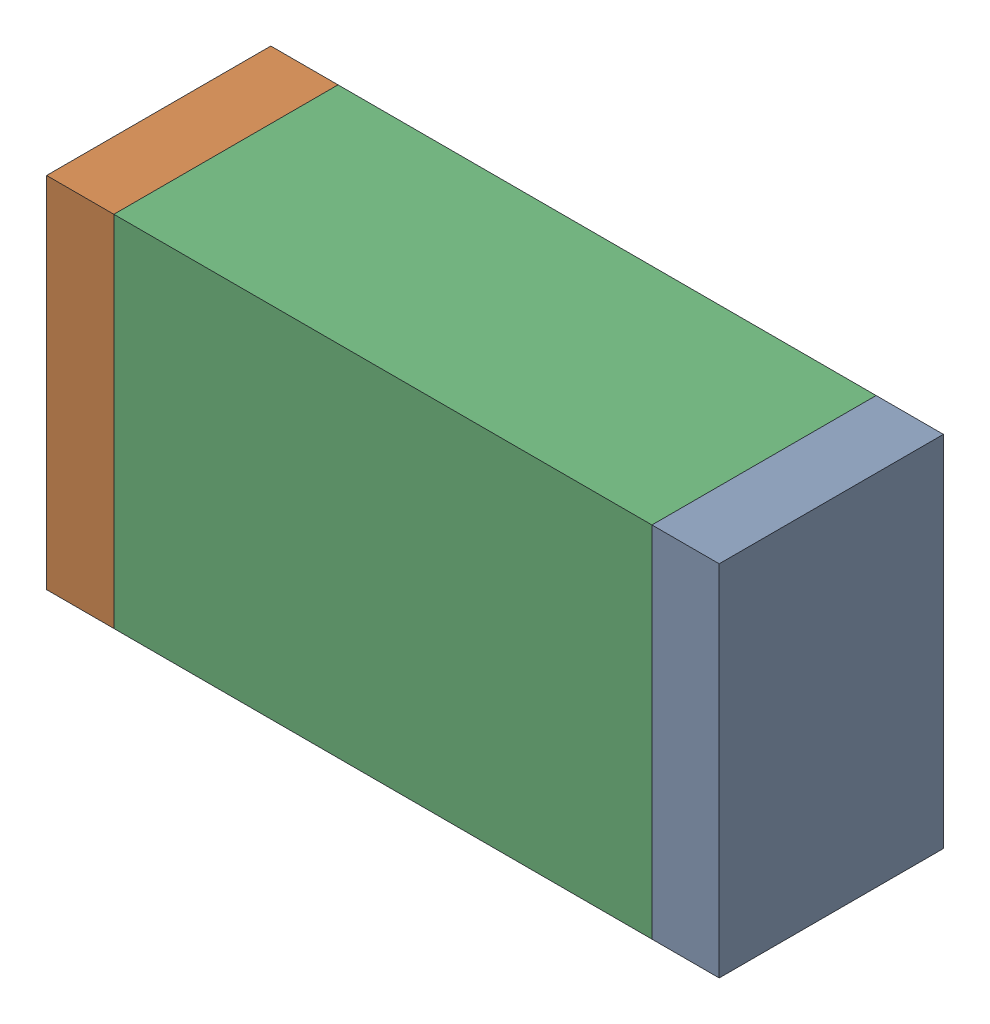
SolidWorks assembly R2, configuration Default. Lengths in mm.
Overall size (1.5 0.8 0.5).
6 component instances, 2 part files, 0 mates.
Components (placement in the parent):
- 836752496-1: 836752496 [Default] at (125.975 9.3 0) size (0.15 0.8 0.5)
  - Extruded_2-1: Extruded_2 [Default] at origin size (0.15 0.8 0.5)
- 836752496-2: 836752496 [Default] at (124.625 9.3 0) size (0.15 0.8 0.5)
  - Extruded_2-1: Extruded_2 [Default] at origin size (0.15 0.8 0.5)
- 836752368-1: 836752368 [Default] at (125.3 9.3 0) size (1.2 0.8 0.5)
  - Extruded-1: Extruded [Default] at origin size (1.2 0.8 0.5)
